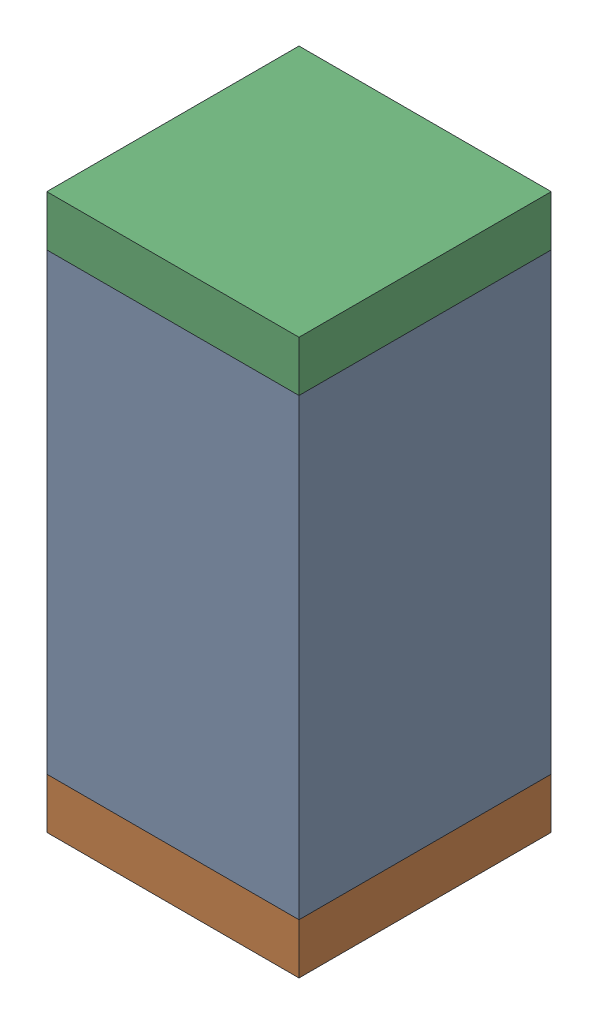
SolidWorks assembly C107, configuration Default. Lengths in mm.
Overall size (0.5 1.1 0.5).
6 component instances, 2 part files, 0 mates.
Components (placement in the parent):
- 791586336-1: 791586336 [Default] at (113.75 76.4 0) size (0.5 0.9 0.5)
  - Extruded_8-1: Extruded_8 [Default] at origin size (0.5 0.9 0.5)
- 810157360-1: 810157360 [Default] at (113.75 75.9 0) size (0.5 0.1 0.5)
  - Extruded_9-1: Extruded_9 [Default] at origin size (0.5 0.1 0.5)
- 810157360-2: 810157360 [Default] at (113.75 76.9 0) size (0.5 0.1 0.5)
  - Extruded_9-1: Extruded_9 [Default] at origin size (0.5 0.1 0.5)
